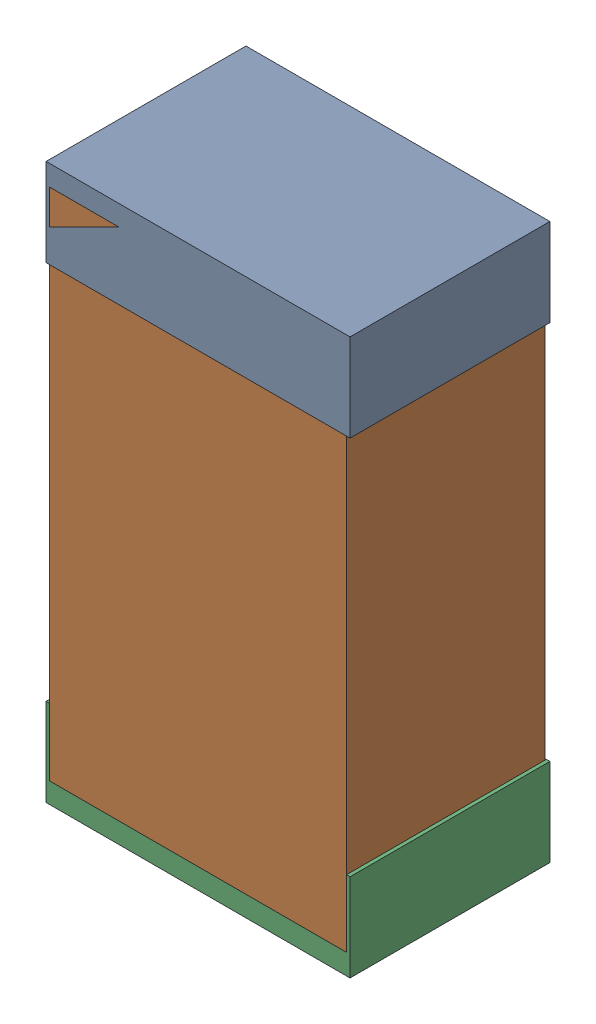
SolidWorks assembly R9Kanaloa_v2.0.0_Power, configuration Default. Lengths in mm.
Overall size (1.3 2.38 0.85).
6 component instances, 2 part files, 0 mates.
Components (placement in the parent):
- 330415056-1: 330415056 [Default] at (114.45 38.9 -1.9574) size (1.3 0.38 0.85)
  - Extruded_2-1: Extruded_2 [Default] at origin size (1.3 0.38 0.85)
- 352877008-1: 352877008 [Default] at (114.45 37.9 -1.9524) size (1.27 2.2 0.85)
  - Extruded_3-1: Extruded_3 [Default] at origin size (1.27 2.2 0.85)
- 330415056-2: 330415056 [Default] at (114.45 36.9 -1.9574) size (1.3 0.38 0.85)
  - Extruded_2-1: Extruded_2 [Default] at origin size (1.3 0.38 0.85)
